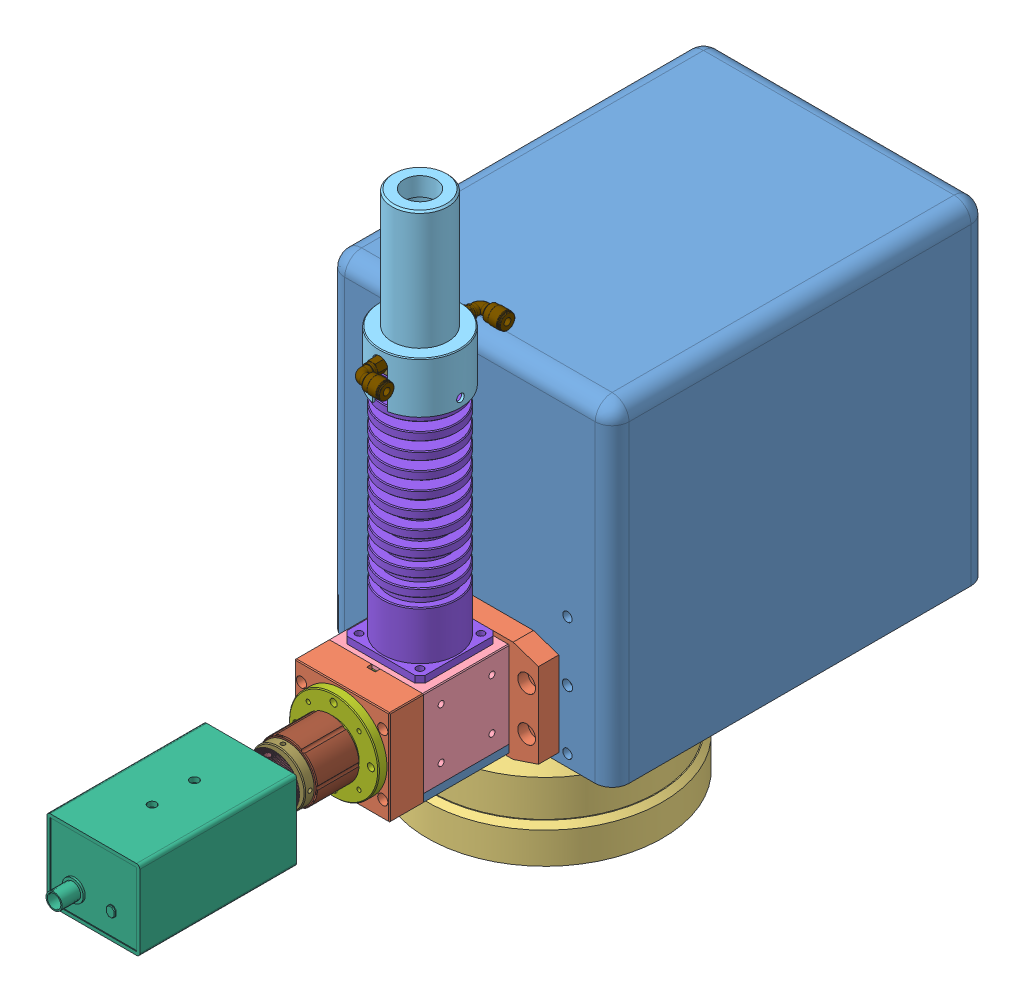
SolidWorks assembly 振镜头, configuration 默认. Lengths in mm.
Overall size (174.05 674.5 475.7).
60 component instances, 42 part files, 0 mates.
Components (placement in the parent):
- 170-550__ASM-1: 170-550__ASM [默认] at (169.8767 309 283.6276) x (-1 0 0) z (0 -1 0)
- 7_QL-_QW_DY_GG-1: 7_QL-_QW_DY_GG [默认] at (18 442.2113 -141.5) x (0 0 1) z (0 -1 0) size (222 168 197.12)
- CCDGUDINGBAN_GG-1: CCDGUDINGBAN_GG [默认] at (37.5 386.7113 -12.5) x (-1 0 0) z (0 0 1) size (90 60 12)
- 170CJ-1: 170CJ [默认] at (-2.55 344.7113 -95.33) size (139 373 139)
- L-DEVLI-SANRE-D_ASM-1: L-DEVLI-SANRE-D_ASM [默认] at (37.5 389.2113 19) x (0 0 -1) z (0 1 0) size (247.2 56 287.5)
  - ZHONGXINKUANGJIA_L-1: ZHONGXINKUANGJIA_L [默认] at origin size (51 56 51)
  - 54X38X5-DS_L_ASM-1: 54X38X5-DS_L_ASM [默认] at (-4.4497 0 -7.4497) x (0.707107 0 -0.707107) z (0 -1 0) size (58 7 42)
    - BABIANYAGAI_L-1: BABIANYAGAI_L [默认] at origin size (58 6.5 42)
    - 54X38DIANPIAN_L-1: 54X38DIANPIAN_L [默认] at (0 1 0) size (54 1 38)
    - 54X38X2BAJIAO_L-1: 54X38X2BAJIAO_L [默认] at (0 2 0) size (54 5 38)
  - KUOSUJING-DS_L_ASM-1: KUOSUJING-DS_L_ASM [默认] at (0.5 0 23) x (0 -1 0) z (-1 0 0) size (46 151 46)
    - CD36F150AW_L-1: CD36F150AW_L [默认] at origin size (46 150 46)
    - CD36_L-1: CD36_L [默认] at (0 10.5 0) x (-1 0 0) z (0 0 1) size (36 6 36)
    - SET-COLLAR_L-1: SET-COLLAR_L [默认] at (0 3 0) size (37 1.5 37)
    - PRESSING-RING_L-1: PRESSING-RING_L [默认] at (0 3 0) x (-1 0 0) z (0 0 1) size (40 4 40)
  - FOCIS-DS_L_ASM-1: FOCIS-DS_L_ASM [默认] at (0.5 0 173) x (-1 0 0) z (0 1 0) size (80.9 14.75 30.75)
    - FOCIS-01_L-1: FOCIS-01_L [默认] at origin size (44 12 12)
    - 10_L-1: 10_L [默认] at (0 5 0) size (9.94 4.21 9.94)
    - FOCIS-SSET01_L-1: FOCIS-SSET01_L [默认] at (0 5 0) x (-1 0 0) z (0 0 1) size (10 4 10)
    - FOCIS-SET_L-1: FOCIS-SET_L [默认] at (0 1 0) x (-1 0 0) z (0 0 1) size (12 5 12)
    - 0XINGQUAN25_L-1: 0XINGQUAN25_L [默认] at (0 0.33 0) size (29.5 2 29.5)
    - O-14_L-1: O-14_L [默认] at (0 0.33 0) size (17.56 1.78 17.56)
    - LJIETOU_L-1: LJIETOU_L [默认] at (17.5 6 0) x (0 -1 0) z (1 0 0) size (9.5 20 22.95)
    - LJIETOU_L-2: LJIETOU_L [默认] at (-17.5 6 0) x (0 1 0) z (-1 0 0) size (9.5 20 22.95)
  - Z-YAGAI_L-1: Z-YAGAI_L [默认] at (0 0 -28) x (0 0 1) z (1 0 0) size (5 56 51)
  - DIANLUZUO_L_ASM-1: DIANLUZUO_L_ASM [默认] at (-45.5 0 -2.5) x (0 0 1) z (0 1 0) size (56 20 56)
    - DIANQIGUDINGZUO_L-1: DIANQIGUDINGZUO_L [默认] at origin size (56 20 56)
    - HB468_L-1: HB468_L [默认] at (0 12 0) x (-1 0 0) z (0 0 1) size (10 6 10)
    - 12YAQUAN_L-1: 12YAQUAN_L [默认] at (0 6 0) x (-1 0 0) z (0 0 1) size (12 5 12)
    - PC-_L_ASM-1: PC-_L_ASM [默认] at (0 6.5 0) size (36 10.5 36)
      - PC-01_FG_L-1: PC-01_FG_L [默认] at origin size (36 1.5 36)
      - PC-D_FG_L-1: PC-D_FG_L [默认] at (13 1.5 -6) size (6 10.5 6)
      - PC-D_FG_L-2: PC-D_FG_L [默认] at (13.435 1.5 4.9497) x (0.707107 0 0.707107) z (-0.707107 0 0.707107) size (6 10.5 6)
      - PC-D_FG_L-3: PC-D_FG_L [默认] at (6 1.5 13) x (0 0 1) z (-1 0 0) size (6 10.5 6)
      - PC-D_FG_L-4: PC-D_FG_L [默认] at (-4.9497 1.5 13.435) x (-0.707107 0 0.707107) z (-0.707107 0 -0.707107) size (6 10.5 6)
      - PC-D_FG_L-5: PC-D_FG_L [默认] at (-13 1.5 6) x (-1 0 0) z (0 0 -1) size (6 10.5 6)
      - PC-D_FG_L-6: PC-D_FG_L [默认] at (-13.435 1.5 -4.9497) x (-0.707107 0 -0.707107) z (0.707107 0 -0.707107) size (6 10.5 6)
      - PC-D_FG_L-7: PC-D_FG_L [默认] at (-6 1.5 -13) x (0 0 -1) z (1 0 0) size (6 10.5 6)
      - PC-D_FG_L-8: PC-D_FG_L [默认] at (4.9497 1.5 -13.435) x (0.707107 0 -0.707107) z (0.707107 0 0.707107) size (6 10.5 6)
  - WEITIANKUAI_L_ASM-1: WEITIANKUAI_L_ASM [默认] at (-50.5 0 -2.5) x (0 -1 0) z (0 0 1) size (53 53.5 53)
    - CD18_L-1: CD18_L [默认] at origin size (53 36 53)
    - XIANWEIKUAI_L-1: XIANWEIKUAI_L [默认] at (0 -5 0) x (0 0 -1) z (-1 0 0) size (15.5 40 15.5)
    - DANGKUAI_L-1: DANGKUAI_L [默认] at (0 -11 7) x (0 -1 0) z (-1 0 0) size (13 2.79 5)
    - DANGKUAI_L-2: DANGKUAI_L [默认] at (0 -11 -7) x (0 -1 0) z (1 0 0) size (13 2.79 5)
    - M28_L-1: M28_L [默认] at (0 -4.5 0) x (0 0 1) z (1 0 0) size (28 13 28)
    - M28WAIQUAN_L-1: M28WAIQUAN_L [默认] at (0 -14.5 0) x (-1 0 0) z (0 0 1)
    - QIANDANGKUAI_L-1: QIANDANGKUAI_L [默认] at (0 -30 0) size (32 6 32)
    - DINGQUAN_L-1: DINGQUAN_L [默认] at (0 -41 0) size (30.03 12 30.03)
    - 18JINGPIAN_L-1: 18JINGPIAN_L [默认] at (0 -2 0) size (18 2.5 18)
    - 18GEQUAN_L-1: 18GEQUAN_L [默认] at (0 -0.5 0) size (18 1 18)
    - M20YAQUAN_L-1: M20YAQUAN_L [默认] at (0 1 0) size (20 4 20)
    - 30OXINGQUAN_L-1: 30OXINGQUAN_L [默认] at (0 4.75 0) x (-1 0 0) z (0 0 -1) size (37.7 3.5 37.7)
  - JU-BAO-DS_L_ASM-1: JU-BAO-DS_L_ASM [默认] at (25.5 0 -2.5) x (0 -1 0) z (0 0 1) size (46 19 46)
    - 07_SS_LEN_BG_L-1: 07_SS_LEN_BG_L [默认] at origin size (46 17 46)
    - 36JINGPIAN_LEN_BG_L-1: 36JINGPIAN_LEN_BG_L [默认] at origin size (36 4 36)
    - 08_SS_LEN_BG_L-1: 08_SS_LEN_BG_L [默认] at (0 9.5 0) x (-1 0 0) z (0 0 1) size (36 5.5 36)
    - 09_SS_LEN_BG_L-1: 09_SS_LEN_BG_L [默认] at (0 3.5 0) x (-1 0 0) z (0 0 1) size (40 4 40)
    - 10_SS_LEN_BG_L-1: 10_SS_LEN_BG_L [默认] at (0 17.5 0) x (-1 0 0) z (0 0 1) size (44 9 44)
  - BAOHUTAO_L-1: BAOHUTAO_L [默认] at (0.5 0 157) x (-1 0 0) z (0 1 0) size (48 100 48)
  - CCD-1: CCD [默认] at (-192.5 0 -2.5) x (0 -1 0) z (0 0 1) size (55 108.2 47)
